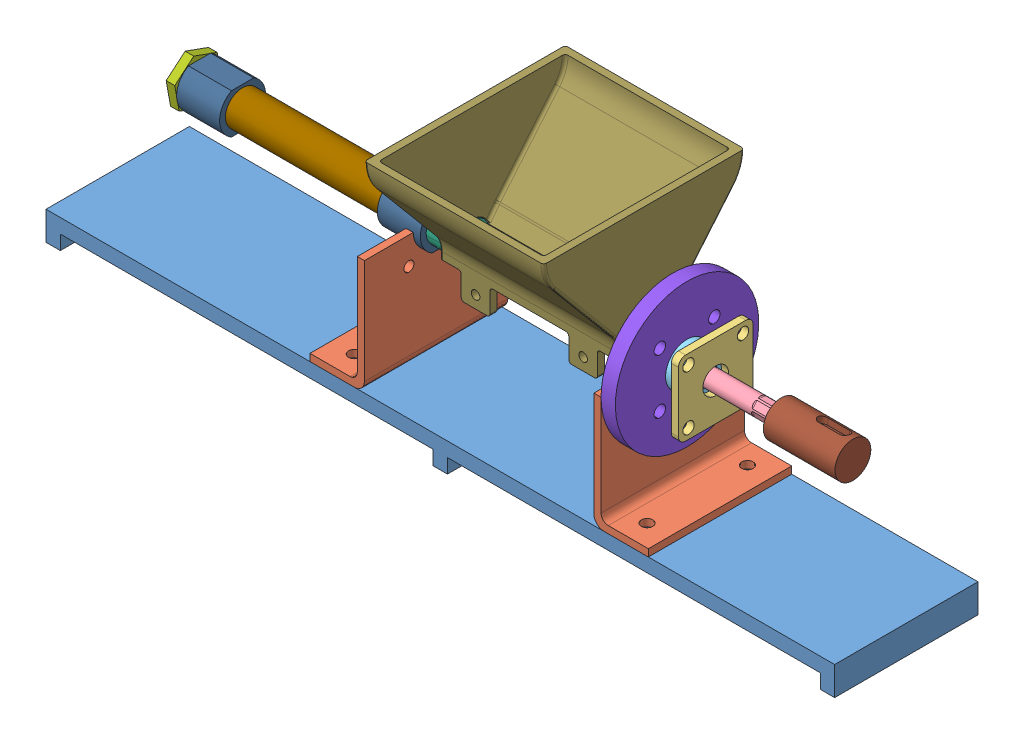
SolidWorks assembly Assem1, configuration Default. Lengths in mm.
Overall size (550 180 141.42).
14 component instances, 12 part files, 35 mates.
Components (placement in the parent):
- basement-1: basement [Default] at (-237.6012 -97.0718 50) size (550 20 100)
- hopper base bracket2-1: hopper base bracket2 [Default] at (144.4988 -87.0718 50) x (0 0 -1) z (1 0 0) size (100 80 38)
- hopper base bracket2-2: hopper base bracket2 [Default] at (-15.5012 -87.0718 -50) x (0 0 1) z (-1 0 0) size (100 80 38)
- auger bearing plate-1: auger bearing plate [Default] at (179.4988 -33.0718 -26) x (0 0 1) z (-1 0 0) size (52 52 5)
- Auger drill bit-1: Auger drill bit [Default] at (240.1574 -7.0718 0) x (1 0 0) z (0 -0.151738 -0.988421) size (438.53 20.47 20.09)
- bronzina-1: bronzina [Default] at (174.4988 -7.0718 0) x (1 0 0) z (0 -0.396707 0.917945) size (15 30 30)
- hopper base2-1: hopper base2 [Default] at (154.4988 -7.0718 0) x (0 0 1) z (-1 0 0) size (24 24 180)
- nozzle2-1: nozzle2 [Default] at (-187.5012 -7.0718 0) x (0 -0.76441 -0.64473) z (1 0 0) size (30 34.64 22)
- pipe flange-1: pipe flange [Default] at (159.4988 -7.0718 0) x (0 -0.707107 0.707107) z (-1 0 0) size (100 100 20)
- pipe nipple2-1: pipe nipple2 [Default] at (-165.5012 -7.0718 0) x (0 -0.630589 -0.776117) z (1 0 0) size (24 24 140)
- raccordo-1: raccordo [Default] at (-10.5012 -7.0718 0) x (0 0 -1) z (-1 0 0) size (32 28 30)
- raccordo-2: raccordo [Default] at (-150.5012 -7.0718 0) x (0 0 1) z (-1 0 0) size (32 28 30)
- accordo motore-2: accordo motore [Default] at (275.1574 -7.0718 0) x (0 0.151738 0.988421) z (-1 0 0) size (25 25 50)
- tramoggia3-1: tramoggia3 [Default] at (124.4988 -7.0718 0) x (0 0 1) z (-1 0 0) size (140 103 125)
Mates (geometry in assembly coordinates):
- Coincidente1: coincident anti-aligned: plane of basement-1 through (-237.6012 -87.0718 -50) normal (0 1 0); plane of hopper base bracket2-1 through (149.4988 -87.0718 50) normal (0 -1 0)
- Concentrico1: concentric aligned: cylinder of basement-1 through (166.5988 -87.0718 35) axis (0 -1 0) radius 4; cylinder of hopper base bracket2-1 through (166.5988 -82.0718 35) axis (0 -1 0) radius 4
- Concentrico2: concentric aligned: cylinder of basement-1 through (166.5988 -87.0718 -35) axis (0 -1 0) radius 4; cylinder of hopper base bracket2-1 through (166.5988 -82.0718 -35) axis (0 -1 0) radius 4
- Coincidente2: coincident anti-aligned: plane of basement-1 through (-237.6012 -87.0718 -50) normal (0 1 0); plane of hopper base bracket2-2 through (-20.5012 -87.0718 -50) normal (0 -1 0)
- Concentrico3: concentric aligned: cylinder of basement-1 through (-37.6012 -87.0718 35) axis (0 -1 0) radius 4; cylinder of hopper base bracket2-2 through (-37.6012 -82.0718 35) axis (0 -1 0) radius 4
- Concentrico4: concentric aligned: cylinder of basement-1 through (-37.6012 -87.0718 -35) axis (0 -1 0) radius 4; cylinder of hopper base bracket2-2 through (-37.6012 -82.0718 -35) axis (0 -1 0) radius 4
- Concentrico5: concentric anti-aligned: cylinder of hopper base bracket2-1 through (149.4988 -7.0718 0) axis (-1 0 0) radius 16; cylinder of hopper base2-1 through (-25.5012 -7.0718 0) axis (1 0 0) radius 12
- Concentrico6: concentric anti-aligned: cylinder of hopper base2-1 through (-25.5012 -7.0718 0) axis (1 0 0) radius 12; cylinder of pipe nipple2-1 through (-25.5012 -7.0718 0) axis (-1 0 0) radius 12
- Concentrico7: concentric anti-aligned: cylinder of pipe nipple2-1 through (-25.5012 -7.0718 0) axis (-1 0 0) radius 12; cylinder of raccordo-1 through (-40.5012 -7.0718 0) axis (1 0 0) radius 16
- Concentrico8: concentric anti-aligned: cylinder of pipe nipple2-1 through (-25.5012 -7.0718 0) axis (-1 0 0) radius 12; cylinder of raccordo-2 through (-180.5012 -7.0718 0) axis (1 0 0) radius 16
- Concentrico9: concentric aligned: cylinder of nozzle2-1 through (-165.5012 -7.0718 0) axis (-1 0 0) radius 12.5; cylinder of pipe nipple2-1 through (-25.5012 -7.0718 0) axis (-1 0 0) radius 12
- Concentrico10: concentric aligned: cylinder of Auger drill bit-1 through (-236.0189 -7.0718 0) axis (-1 0 0) radius 9.9; cylinder of pipe nipple2-1 through (-25.5012 -7.0718 0) axis (-1 0 0) radius 12
- Concentrico11: concentric aligned: cylinder of hopper base2-1 through (-25.5012 -7.0718 0) axis (1 0 0) radius 12; cylinder of pipe flange-1 through (139.4988 -7.0718 0) axis (1 0 0) radius 15
- Concentrico15: concentric anti-aligned: cylinder of hopper base bracket2-1 through (149.4988 -26.0718 19) axis (-1 0 0) radius 3.5; cylinder of auger bearing plate-1 through (174.4988 -26.0718 19) axis (1 0 0) radius 4
- Concentrico16: concentric anti-aligned: cylinder of hopper base bracket2-1 through (149.4988 -26.0718 -19) axis (-1 0 0) radius 3.5; cylinder of auger bearing plate-1 through (174.4988 -26.0718 -19) axis (1 0 0) radius 4
- Concentrico17: concentric anti-aligned: cylinder of hopper base bracket2-1 through (149.4988 -26.0718 -19) axis (-1 0 0) radius 3.5; cylinder of pipe flange-1 through (149.4988 -26.0718 -19) axis (1 0 0) radius 4
- Concentrico18: concentric anti-aligned: cylinder of hopper base bracket2-1 through (149.4988 -26.0718 19) axis (-1 0 0) radius 3.5; cylinder of pipe flange-1 through (149.4988 -26.0718 19) axis (1 0 0) radius 4
- Distanza1: distance = 15 mm anti-aligned: plane of nozzle2-1 through (-165.5012 -7.0718 0) normal (1 0 0); plane of raccordo-2 through (-180.5012 -7.0718 0) normal (-1 0 0)
- Distanza2: distance = 15 mm anti-aligned: plane of raccordo-2 through (-150.5012 -7.0718 0) normal (1 0 0); plane of pipe nipple2-1 through (-165.5012 -7.0718 0) normal (-1 0 0)
- Distanza3: distance = 15 mm anti-aligned: plane of raccordo-1 through (-40.5012 -7.0718 0) normal (-1 0 0); plane of pipe nipple2-1 through (-25.5012 -7.0718 0) normal (1 0 0)
- Distanza4: distance = 15 mm anti-aligned: plane of raccordo-1 through (-10.5012 -7.0718 0) normal (1 0 0); plane of hopper base2-1 through (-25.5012 -7.0718 0) normal (-1 0 0)
- Distanza5: distance = 15 mm anti-aligned: plane of hopper base2-1 through (154.4988 -7.0718 0) normal (1 0 0); plane of pipe flange-1 through (139.4988 -7.0718 0) normal (-1 0 0)
- Coincidente10: coincident anti-aligned: plane of Auger drill bit-1 through (240.1574 -2.7115 -10.5469) normal (0 -0.625619 -0.780129); plane of accordo motore-2 through (240.1574 -8.0355 -6.2773) normal (0 0.625619 0.780129)
- Coincidente11: coincident: cone of Auger drill bit-1 through (170.8725 -7.0718 0) axis (1 0 0); circle of bronzina-1
- Coincidente12: coincident anti-aligned: plane of auger bearing plate-1 through (174.4988 -28.0718 -21) normal (-1 0 0); plane of bronzina-1 through (174.4988 6.6973 5.9506) normal (1 0 0)
- Coincidente13: coincident anti-aligned: plane of bronzina-1 through (159.4988 2.2358 4.0225) normal (-1 0 0); plane of pipe flange-1 through (159.4988 -7.0718 0) normal (1 0 0)
- Coincidente14: coincident anti-aligned: plane of hopper base bracket2-1 through (149.4988 -7.0718 0) normal (1 0 0); plane of pipe flange-1 through (149.4988 -7.0718 0) normal (-1 0 0)
- Parallelo1: parallel aligned: plane of basement-1 through (-237.6012 -87.0718 -50) normal (0 1 0); plane of raccordo-1 through (-10.5012 6.9282 18.8635) normal (0 1 0)
- Parallelo2: parallel aligned: plane of raccordo-1 through (-10.5012 6.9282 18.8635) normal (0 1 0); plane of raccordo-2 through (-150.5012 6.9282 -17.7945) normal (0 1 0)
- Coincidente20: coincident anti-aligned: plane of Auger drill bit-1 through (240.1574 -13.0024 0.9104) normal (1 0 0); plane of accordo motore-2 through (240.1574 -2.1174 -3.9732) normal (-1 0 0)
- Concentrico26: concentric anti-aligned: cylinder of Auger drill bit-1 through (-236.0189 -7.0718 0) axis (-1 0 0) radius 6; cylinder of accordo motore-2 through (225.1574 -7.0718 0) axis (1 0 0) radius 12.5
- Coincidente21: coincident anti-aligned: plane of hopper base2-1 through (9.4988 -7.0718 20) normal (0 1 0); plane of tramoggia3-1 through (9.4988 -7.0718 -10.5) normal (0 -1 0)
- Coincidente22: coincident aligned: plane of hopper base2-1 through (124.4988 4.9282 20) normal (-1 0 0); plane of tramoggia3-1 through (124.4988 -7.0718 35.5) normal (-1 0 0)
- Concentrico27: concentric anti-aligned: cylinder of hopper base2-1 through (-25.5012 -7.0718 0) axis (1 0 0) radius 12; circle of tramoggia3-1
- Parallelo3: parallel anti-aligned: plane of basement-1 through (-237.6012 -87.0718 -50) normal (0 1 0); plane of tramoggia3-1 through (9.4988 -12.0718 -17.5) normal (0 -1 0)
